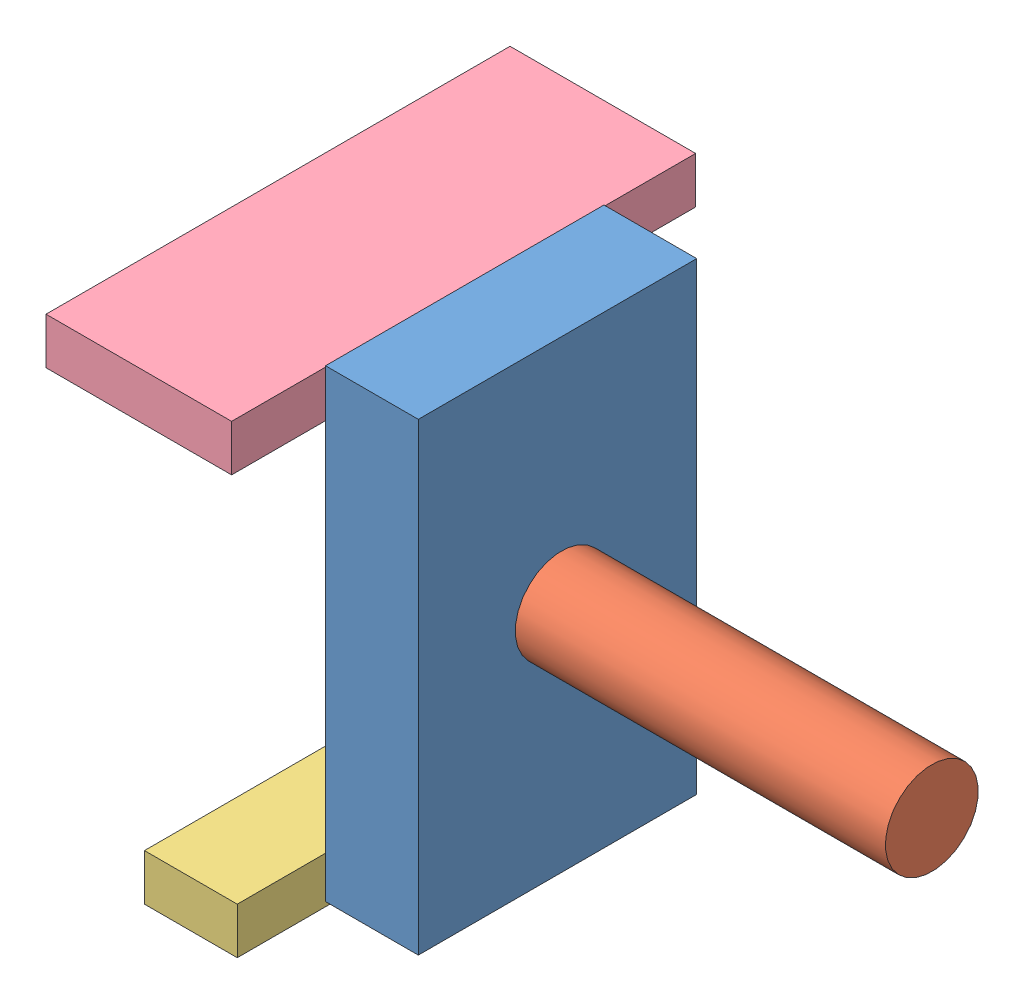
SolidWorks assembly Magnetic holder, configuration Default. Lengths in mm.
Overall size (69.88 50.49 50.61).
5 component instances, 4 part files, 2 mates.
Components (placement in the parent):
- Magnetic base-1: Magnetic base [Default] at (-8.0303 67.2287 8.7656) x (1 0 0) z (0 -1 0) size (50 30 50)
  - card-1: card [Default] at (10.9232 42.8222 68.5375) x (0 0 -1) z (1 0 0) size (50 30 10)
  - Magnetic rod-1: Magnetic rod [Default] at (10.8054 27.3741 45.5694) x (1 0 0) z (0 -0.696613 0.717447) size (50 10 10)
- Part1-1: Part1 [Default] at (-7.1071 -3.835 61.0956) x (0 0 -1) z (0 1 0) size (50 10 5)
- Part2-1: Part2 [Default] at (-17.1071 41.5226 61.7042) x (0 0 -1) z (0 1 0) size (50 20 5)
Mates (geometry in assembly coordinates):
- Coincident1: coincident: plane of assembly; plane of assembly; plane of Magnetic base-1/card-1 through (2.8929 -1.3088 51.5878) normal (-1 0 0); plane of Part2-1 through (2.8929 46.5226 61.7042) normal (1 0 0)
- Coincident2: coincident: plane of assembly; plane of assembly; plane of Magnetic base-1/card-1 through (2.8929 -1.3088 51.5878) normal (-1 0 0); plane of Part1-1 through (2.8929 1.165 61.0956) normal (1 0 0)
